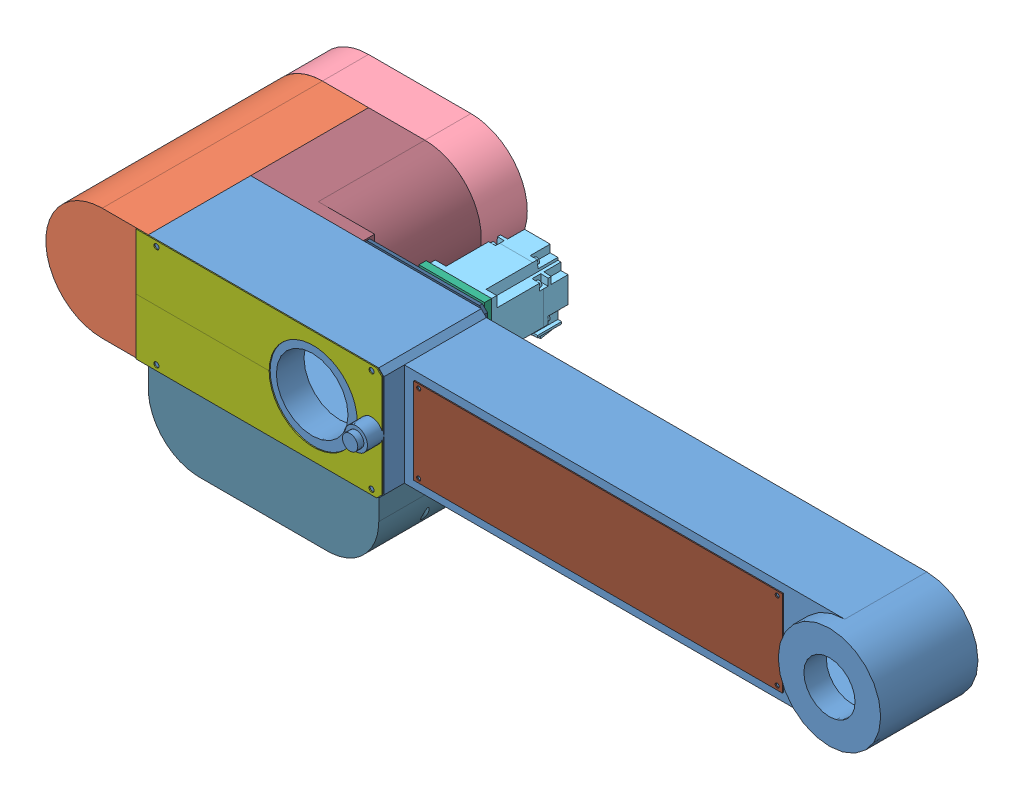
SolidWorks assembly [KHAU-----3], configuration Default. Lengths in mm.
Overall size (810 181.77 283).
16 component instances, 14 part files, 46 mates.
Components (placement in the parent):
- [K3]Thân.stp-1: [K3]Thân.stp [Default] at (125.4298 449.8157 564.7733) size (710 110 122)
- [K3[Nắp.stp-1: [K3[Nắp.stp [Default] at (-79.5702 449.8157 584.7733) x (0 0 -1) z (1 0 0) size (215 110 100)
- [K3]Căn_chỉnh_ĐC.stp-1: [K3]Căn_chỉnh_ĐC.stp [Default] at (-79.5702 449.8157 369.7733) x (0 -1 0) z (-1 0 0) size (88 2.5 80)
- [K3]Đỡ DC.stp-1: [K3]Đỡ DC.stp [Default] at (20.4298 449.8157 369.7733) x (0 0 -1) z (1 0 0) size (45 110 210)
- [K3]Động_cơ.stp-1: [K3]Động_cơ.stp [Default] at (-69.5702 449.8157 372.2733) x (0 1 0) z (0 0 -1) size (60 68.8 106.6)
- [K3]Mặt_Bích.stp-1: [K3]Mặt_Bích.stp [Default] at (133.662 451.5834 449.7733) x (1 0 0) z (0 -1 0) size (64 32 64)
- [K3]Nap.stp-1: [K3]Nap.stp [Default] at (194.4298 449.8157 585.7733) x (0 0 -1) z (1 0 0) size (1 55 240)
- [K3]Nắp_Đầu.stp-1: [K3]Nắp_Đầu.stp [Default] at (625.4298 449.8157 484.7733) x (0 0 1) z (-1 0 0) size (1 94.92 95)
- [K3]Nắp_Đỡ DC.stp-1: [K3]Nắp_Đỡ DC.stp [Default] at (-29.5702 449.8157 323.7733) x (0 0 1) z (-1 0 0) size (1 105 205)
- [K3]Nắp_ĐộngCơ.stp-1: [K3]Nắp_ĐộngCơ.stp [Default] at (133.662 451.5834 481.7733) x (0 0 1) z (-1 0 0) size (3 110 120)
- [K3]Nắp_Thân.stp-1: [K3]Nắp_Thân.stp [Default] at (385.4298 449.8157 565.7733) x (0 -1 0) z (1 0 0) size (84 1 360)
- [K3]Nắp_Thân_22.stp-1: [K3]Nắp_Thân_22.stp [Default] at (385.4298 450.3157 484.7733) x (0 1 0) z (-1 0 0) size (88 1 370)
- [K3]Ong.stp-1: [K3]Ong.stp [Default] at (20.4298 449.8157 484.7733) x (0 0 -1) z (1 0 0) size (115 110 110)
- [K3]Ốp.stp-1: [K3]Ốp.stp [Default] at (77.9298 324.8157 534.7733) x (0 0 -1) z (1 0 0) size (100 70 225)
- [K3]Động_cơ.stp-2: [K3]Động_cơ.stp [Default] at (133.662 451.5834 449.7733) size (60 68.8 106.6)
- [K3]Nap.stp-2: [K3]Nap.stp [Default] at (194.4298 449.8157 584.7733) x (0 0 1) z (1 0 0) size (1 55 240)
Mates (geometry in assembly coordinates):
- Coincident1: coincident anti-aligned: plane of [K3]Thân.stp-1 through (190.4298 394.8157 564.7733) normal (0 -1 0); plane of [K3]Ốp.stp-1 through (-34.5702 394.8157 534.7733) normal (0 1 0)
- Coincident2: coincident aligned: plane of [K3]Thân.stp-1 through (-34.5702 394.8157 564.7733) normal (-1 0 0); plane of [K3]Ốp.stp-1 through (-34.5702 374.8157 534.7733) normal (-1 0 0)
- Coincident3: coincident aligned: plane of [K3]Thân.stp-1 through (80.4298 449.8157 584.7733) normal (0 0 1); plane of [K3]Ốp.stp-1 through (77.9298 359.8157 584.7733) normal (0 0 1)
- Coincident4: coincident anti-aligned: plane of [K3]Thân.stp-1 through (-34.5702 394.8157 564.7733) normal (-1 0 0); plane of [K3[Nắp.stp-1 through (-34.5702 504.8157 584.7733) normal (1 0 0)
- Coincident5: coincident aligned: plane of [K3]Thân.stp-1 through (80.4298 449.8157 584.7733) normal (0 0 1); plane of [K3[Nắp.stp-1 through (-84.5702 449.8157 584.7733) normal (0 0 1)
- Coincident6: coincident aligned: plane of [K3]Thân.stp-1 through (-34.5702 504.8157 564.7733) normal (0 1 0); plane of [K3[Nắp.stp-1 through (-79.5702 504.8157 584.7733) normal (0 1 0)
- Coincident7: coincident anti-aligned: plane of [K3]Thân.stp-1 through (400.4298 449.8157 484.7733) normal (0 0 -1); plane of [K3]Ong.stp-1 through (20.4298 449.8157 484.7733) normal (0 0 1)
- Coincident8: coincident aligned: plane of [K3]Thân.stp-1 through (-34.5702 504.8157 564.7733) normal (0 1 0); plane of [K3]Ong.stp-1 through (-34.5702 504.8157 484.7733) normal (0 1 0)
- Coincident9: coincident anti-aligned: plane of [K3[Nắp.stp-1 through (-34.5702 504.8157 584.7733) normal (1 0 0); plane of [K3]Ong.stp-1 through (-34.5702 394.8157 484.7733) normal (-1 0 0)
- Coincident10: coincident anti-aligned: plane of [K3]Thân.stp-1 through (400.4298 449.8157 484.7733) normal (0 0 -1); plane of [K3]Nắp_ĐộngCơ.stp-1 through (133.662 451.5834 484.7733) normal (0 0 1)
- Parallel1: parallel aligned: plane of [K3]Thân.stp-1 through (-34.5702 504.8157 564.7733) normal (0 1 0); plane of [K3]Nắp_ĐộngCơ.stp-1 through (193.662 506.5834 481.7733) normal (0 1 0)
- Concentric1: concentric anti-aligned: cylinder of [K3]Thân.stp-1 through (108.9133 476.3322 1213.5284) axis (0 0 -1) radius 1.621; cylinder of [K3]Nắp_ĐộngCơ.stp-1 through (108.9133 476.3322 321.9574) axis (0 0 1) radius 2.067
- Concentric2: concentric anti-aligned: cylinder of [K3]Nắp_ĐộngCơ.stp-1 through (133.662 451.5834 484.7733) axis (0 0 -1) radius 20; cylinder of [K3]Động_cơ.stp-2 through (133.662 451.5834 466.2733) axis (0 0 1) radius 7
- Concentric3: concentric anti-aligned: cylinder of [K3]Nắp_ĐộngCơ.stp-1 through (158.4107 476.3322 321.9574) axis (0 0 1) radius 2.067; cylinder of [K3]Động_cơ.stp-2 through (158.4107 476.3322 446.2733) axis (0 0 -1) radius 2.9
- Coincident13: coincident anti-aligned: plane of [K3]Mặt_Bích.stp-1 through (133.662 451.5834 481.7733) normal (0 0 1); plane of [K3]Nắp_ĐộngCơ.stp-1 through (133.662 451.5834 481.7733) normal (0 0 -1)
- Parallel2: parallel aligned: plane of [K3]Thân.stp-1 through (-34.5702 504.8157 564.7733) normal (0 1 0); plane of [K3]Mặt_Bích.stp-1 through (165.662 483.5834 474.7733) normal (0 1 0)
- Concentric4: concentric aligned: cylinder of [K3]Mặt_Bích.stp-1 through (158.4107 476.3322 385.7733) axis (0 0 1) radius 2.067; cylinder of [K3]Nắp_ĐộngCơ.stp-1 through (158.4107 476.3322 321.9574) axis (0 0 1) radius 2.067
- Concentric5: concentric anti-aligned: cylinder of [K3]Mặt_Bích.stp-1 through (133.662 451.5834 481.7733) axis (0 0 -1) radius 25; cylinder of [K3]Động_cơ.stp-2 through (133.662 451.5834 451.2733) axis (0 0 1) radius 25
- Parallel3: parallel aligned: plane of [K3]Thân.stp-1 through (-34.5702 504.8157 564.7733) normal (0 1 0); plane of [K3]Động_cơ.stp-2 through (133.662 481.5834 423.4733) normal (0 1 0)
- Coincident16: coincident anti-aligned: plane of [K3]Mặt_Bích.stp-1 through (133.662 451.5834 449.7733) normal (0 0 -1); plane of [K3]Động_cơ.stp-2 through (133.662 451.5834 449.7733) normal (0 0 1)
- Coincident18: coincident anti-aligned: plane of [K3]Căn_chỉnh_ĐC.stp-1 through (-79.5702 449.8157 369.7733) normal (0 0 -1); plane of [K3]Đỡ DC.stp-1 through (-29.5702 449.8157 369.7733) normal (0 0 1)
- Concentric14: concentric aligned: cylinder of [K3]Căn_chỉnh_ĐC.stp-1 through (-69.5702 449.8157 369.7733) axis (0 0 1) radius 25; cylinder of [K3]Đỡ DC.stp-1 through (-69.5702 449.8157 364.7733) axis (0 0 1) radius 20
- Parallel6: parallel aligned: plane of [K3]Căn_chỉnh_ĐC.stp-1 through (-101.5702 405.8157 369.7733) normal (0 -1 0); plane of [K3]Đỡ DC.stp-1 through (20.4298 394.8157 369.7733) normal (0 -1 0)
- Concentric15: concentric anti-aligned: cylinder of [K3]Đỡ DC.stp-1 through (-69.5702 449.8157 364.7733) axis (0 0 1) radius 20; cylinder of [K3]Động_cơ.stp-1 through (-69.5702 449.8157 355.7733) axis (0 0 -1) radius 7
- Concentric16: concentric aligned: cylinder of [K3]Căn_chỉnh_ĐC.stp-1 through (-44.8215 474.5644 253.3184) axis (0 0 1) radius 2.067; cylinder of [K3]Động_cơ.stp-1 through (-44.8215 474.5644 375.7733) axis (0 0 1) radius 2.9
- Coincident21: coincident anti-aligned: plane of [K3]Căn_chỉnh_ĐC.stp-1 through (-79.5702 449.8157 372.2733) normal (0 0 1); plane of [K3]Động_cơ.stp-1 through (-69.5702 449.8157 372.2733) normal (0 0 -1)
- Coincident22: coincident anti-aligned: plane of [K3]Đỡ DC.stp-1 through (-29.5702 449.8157 369.7733) normal (0 0 1); plane of [K3]Ong.stp-1 through (20.4298 449.8157 369.7733) normal (0 0 -1)
- Concentric17: concentric aligned: cylinder of [K3[Nắp.stp-1 through (-79.5702 449.8157 584.7733) axis (0 0 -1) radius 55; cylinder of [K3]Đỡ DC.stp-1 through (-79.5702 449.8157 369.7733) axis (0 0 -1) radius 55
- Concentric18: concentric aligned: cylinder of [K3]Đỡ DC.stp-1 through (20.4298 449.8157 369.7733) axis (0 0 -1) radius 55; cylinder of [K3]Ong.stp-1 through (20.4298 449.8157 473.7733) axis (0 0 -1) radius 55
- Coincident23: coincident anti-aligned: plane of [K3]Đỡ DC.stp-1 through (-29.5702 449.8157 324.7733) normal (0 0 -1); plane of [K3]Nắp_Đỡ DC.stp-1 through (-29.5702 449.8157 324.7733) normal (0 0 1)
- Concentric19: concentric anti-aligned: cylinder of [K3]Đỡ DC.stp-1 through (20.4298 449.8157 369.7733) axis (0 0 -1) radius 55; cylinder of [K3]Nắp_Đỡ DC.stp-1 through (20.4298 449.8157 323.7733) axis (0 0 1) radius 52.5
- Concentric20: concentric anti-aligned: cylinder of [K3]Đỡ DC.stp-1 through (-79.5702 449.8157 369.7733) axis (0 0 -1) radius 55; cylinder of [K3]Nắp_Đỡ DC.stp-1 through (-79.5702 449.8157 323.7733) axis (0 0 1) radius 52.5
- Concentric27: concentric aligned: cylinder of [K3]Thân.stp-1 through (560.4298 487.8157 1207.684) axis (0 0 -1) radius 1.621; cylinder of [K3]Nắp_Thân_22.stp-1 through (560.4298 487.8157 864.0955) axis (0 0 -1) radius 2
- Coincident26: coincident anti-aligned: plane of [K3]Thân.stp-1 through (400.4298 449.8157 484.7733) normal (0 0 -1); plane of [K3]Nắp_Thân_22.stp-1 through (385.4298 450.3157 484.7733) normal (0 0 1)
- Parallel11: parallel aligned: plane of [K3]Thân.stp-1 through (195.4298 499.8157 564.7733) normal (0 1 0); plane of [K3]Nắp_Thân_22.stp-1 through (200.4298 494.3157 484.7733) normal (0 1 0)
- Coincident28: coincident anti-aligned: plane of [K3]Thân.stp-1 through (400.4298 449.8157 564.7733) normal (0 0 1); plane of [K3]Nắp_Thân.stp-1 through (385.4298 449.8157 564.7733) normal (0 0 -1)
- Concentric28: concentric aligned: cylinder of [K3]Thân.stp-1 through (560.4298 487.8157 1207.684) axis (0 0 -1) radius 1.621; cylinder of [K3]Nắp_Thân.stp-1 through (560.4298 487.8157 934.4447) axis (0 0 -1) radius 2
- Parallel12: parallel aligned: plane of [K3]Thân.stp-1 through (195.4298 499.8157 564.7733) normal (0 1 0); plane of [K3]Nắp_Thân.stp-1 through (205.4298 491.8157 565.7733) normal (0 1 0)
- Coincident30: coincident anti-aligned: plane of [K3]Thân.stp-1 through (625.4298 449.8157 485.7733) normal (0 0 -1); plane of [K3]Nắp_Đầu.stp-1 through (625.4298 449.8157 485.7733) normal (0 0 1)
- Concentric29: concentric anti-aligned: cylinder of [K3]Thân.stp-1 through (625.4298 494.8157 1208.684) axis (0 0 -1) radius 1.621; cylinder of [K3]Nắp_Đầu.stp-1 through (625.4298 494.8157 484.7733) axis (0 0 1) radius 2
- Concentric30: concentric anti-aligned: cylinder of [K3]Thân.stp-1 through (184.4298 449.8157 584.7733) axis (0 0 1) radius 11; cylinder of [K3]Nap.stp-1 through (184.4298 449.8157 585.7733) axis (0 0 -1) radius 6.5
- Coincident32: coincident anti-aligned: plane of [K3]Thân.stp-1 through (80.4298 449.8157 584.7733) normal (0 0 1); plane of [K3]Nap.stp-1 through (74.4298 477.3157 584.7733) normal (0 0 -1)
- Coincident33: coincident aligned: plane of [K3]Thân.stp-1 through (-34.5702 504.8157 564.7733) normal (0 1 0); plane of [K3]Nap.stp-1 through (-45.5702 504.8157 585.7733) normal (0 1 0)
- Concentric32: concentric aligned: cylinder of [K3]Thân.stp-1 through (184.4298 449.8157 584.7733) axis (0 0 1) radius 11; cylinder of [K3]Nap.stp-2 through (184.4298 449.8157 584.7733) axis (0 0 1) radius 6.5
- Coincident37: coincident anti-aligned: plane of [K3]Thân.stp-1 through (80.4298 449.8157 584.7733) normal (0 0 1); plane of [K3]Nap.stp-2 through (74.4298 422.3157 584.7733) normal (0 0 -1)
- Coincident39: coincident anti-aligned: plane of [K3]Nap.stp-1 through (84.4298 449.8157 585.7733) normal (0 -1 0); plane of [K3]Nap.stp-2 through (84.4298 449.8157 584.7733) normal (0 1 0)
